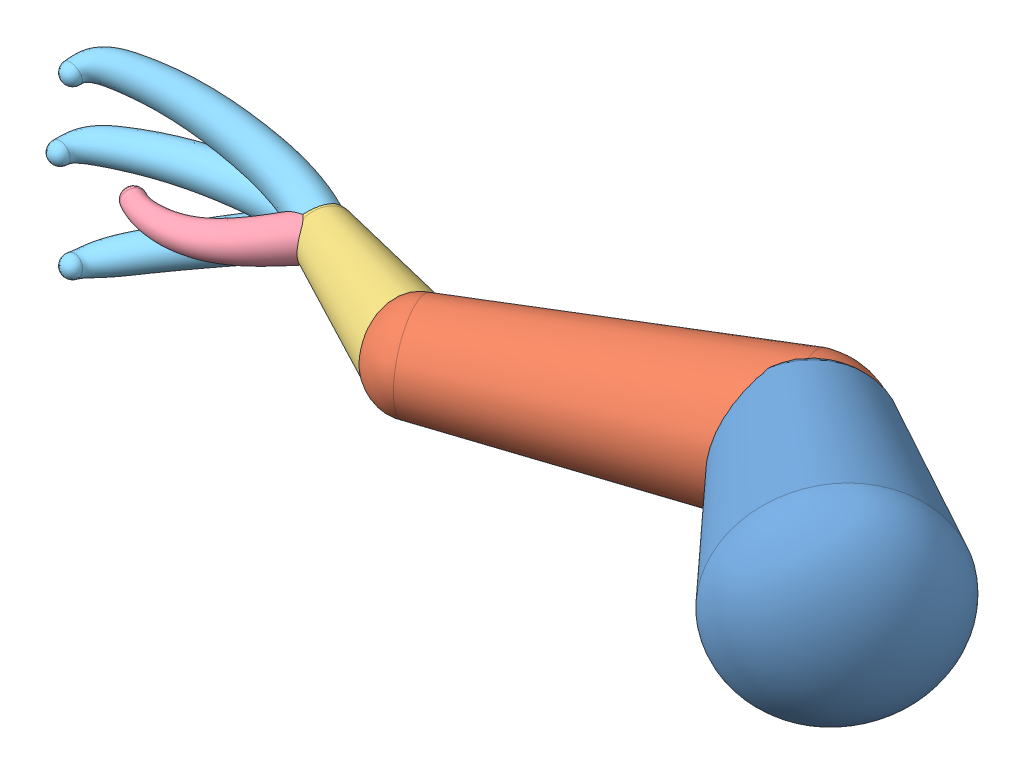
SolidWorks assembly Leg Assembly, configuration Default. Lengths in mm.
Overall size (129.61 33.55 42.78).
5 component instances, 5 part files, 8 mates.
Components (placement in the parent):
- Upper Leg-1: Upper Leg [Default] at (125.3079 0.7176 54.3308) x (0 1 0) z (1 0 0) size (33.55 41.36 43.09)
- Mid Leg-1: Mid Leg [Default] at (125.3079 0.7176 54.3308) x (0 1 0) z (1 0 0) size (20 37.04 56.03)
- Lower Leg-1: Lower Leg [Default] at (125.3079 0.7176 54.3308) x (0 1 0) z (1 0 0) size (13.26 19.61 34)
- Thumb-1: Thumb [Default] at (125.1385 0.7176 54.542) x (0 1 0) z (1 0 0) size (6.01 15.63 23.37)
- Finger-1: Finger [Default] at (125.1385 0.7176 54.542) x (0 1 0) z (1 0 0) size (29.58 16.17 35)
Mates (geometry in assembly coordinates):
- Coincident4: coincident aligned: line of Upper Leg-1 through (-24.1512 0.7176 -15.6136) axis (0 1 0); line of Mid Leg-1 through (-24.1512 0.7176 -15.6136) axis (0 1 0)
- Coincident5: coincident aligned: plane of Upper Leg-1; plane of Mid Leg-1
- Coincident7: coincident aligned: line of Mid Leg-1 through (-64.0131 0.7176 2.6349) axis (0 1 0); line of Lower Leg-1 through (-64.0131 0.7176 2.6349) axis (0 1 0)
- Coincident8: coincident aligned: plane of Mid Leg-1; plane of Lower Leg-1
- Coincident10: coincident aligned: line of Lower Leg-1 through (-86.5726 0.7176 -6.084) axis (0 1 0); line of Thumb-1 through (-86.5726 0.7176 -6.084) axis (0 1 0)
- Coincident11: coincident aligned: plane of Lower Leg-1; plane of Thumb-1
- Coincident13: coincident aligned: line of Lower Leg-1 through (-86.5726 0.7176 -6.084) axis (0 1 0); line of Finger-1 through (-86.5726 0.7176 -6.084) axis (0 1 0)
- Coincident14: coincident aligned: plane of Lower Leg-1; plane of Finger-1
